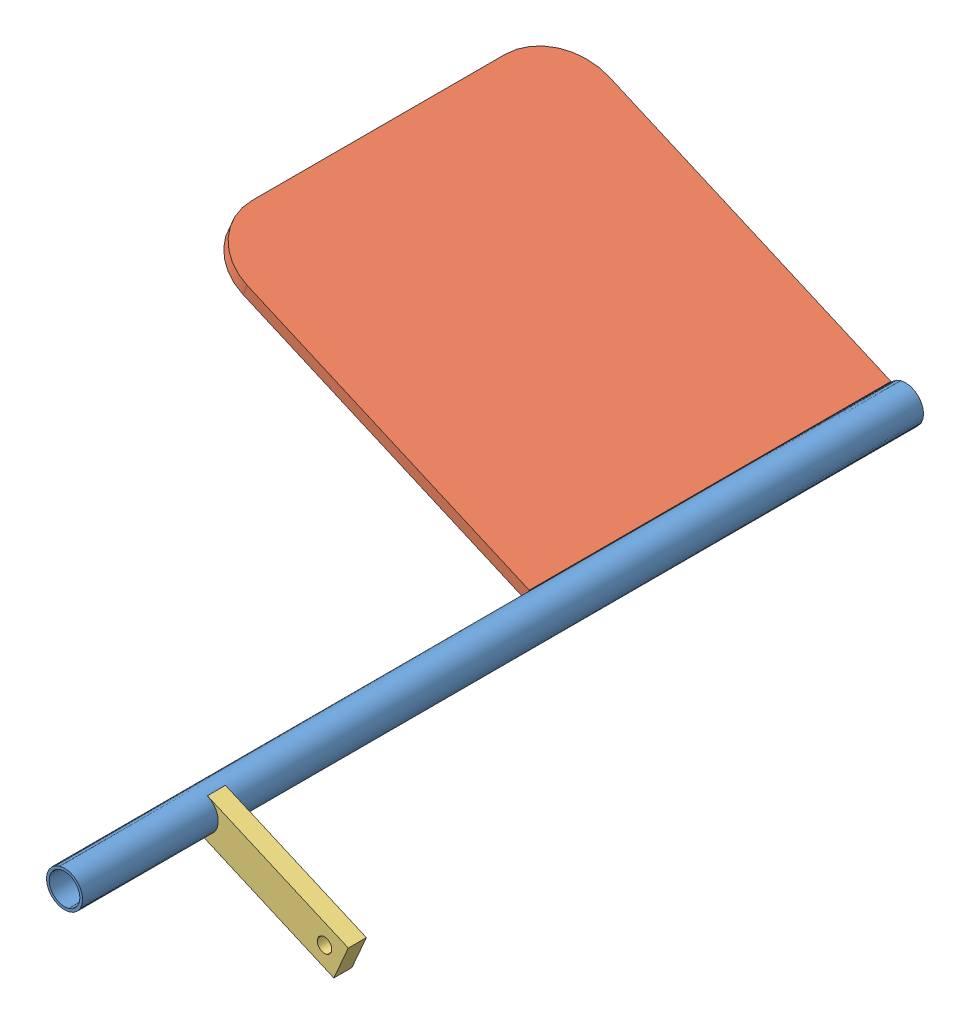
SolidWorks assembly Assemblage1, configuration Défaut. Lengths in mm.
Overall size (275.68 129.65 465).
3 component instances, 3 part files, 6 mates.
Components (placement in the parent):
- Tube 20x1.5-1: Tube 20x1.5 [Défaut] at (-30.4914 -1.6375 -232.5) size (20 20 465)
- safran-1: safran [Défaut] at (-221.8655 84.8714 -232.5) x (0.916632 -0.399732 0) z (-0.399732 -0.916632 0) size (200 200 6)
- biellette 20x10-1: biellette 20x10 [Défaut] at (-35.6604 11.5261 147.5) x (0.916632 -0.399732 0) z (0 0 1) size (85 20 10)
Mates (geometry in assembly coordinates):
- Tangent1: tangent anti-aligned: cylinder of Tube 20x1.5-1 through (-30.4914 -1.6375 232.5) axis (0 0 -1) radius 10; plane of safran-1 through (-40.9375 -0.5748 -232.5) normal (0.916632 -0.399732 0)
- Distance4: distance = 0.5 mm: line of safran-1 through (-40.9375 -0.5748 -232.5) axis (0 0 1); cylinder of Tube 20x1.5-1 through (-30.4914 -1.6375 232.5) axis (0 0 -1) radius 10
- Coïncidente6: coincident aligned: plane of Tube 20x1.5-1 through (-30.4914 -1.6375 -232.5) normal (0 0 -1); plane of safran-1 through (-196.7649 67.3797 -232.5) normal (0 0 -1)
- Coaxiale1: concentric aligned: cylinder of Tube 20x1.5-1 through (-30.4914 -1.6375 232.5) axis (0 0 -1) radius 10; cylinder of biellette 20x10-1 through (-30.4914 -1.6375 157.5) axis (0 0 -1) radius 10
- Distance5: distance = 75 mm aligned: plane of Tube 20x1.5-1 through (-30.4914 -1.6375 232.5) normal (0 0 1); plane of biellette 20x10-1 through (-30.4914 -1.6375 157.5) normal (0 0 1)
- Parallèle3: parallel anti-aligned: line of safran-1 through (-40.9375 -0.5748 -32.5) axis (-0.916632 0.399732 0); line of biellette 20x10-1 through (-34.4887 -10.8038 157.5) axis (0.916632 -0.399732 0)
